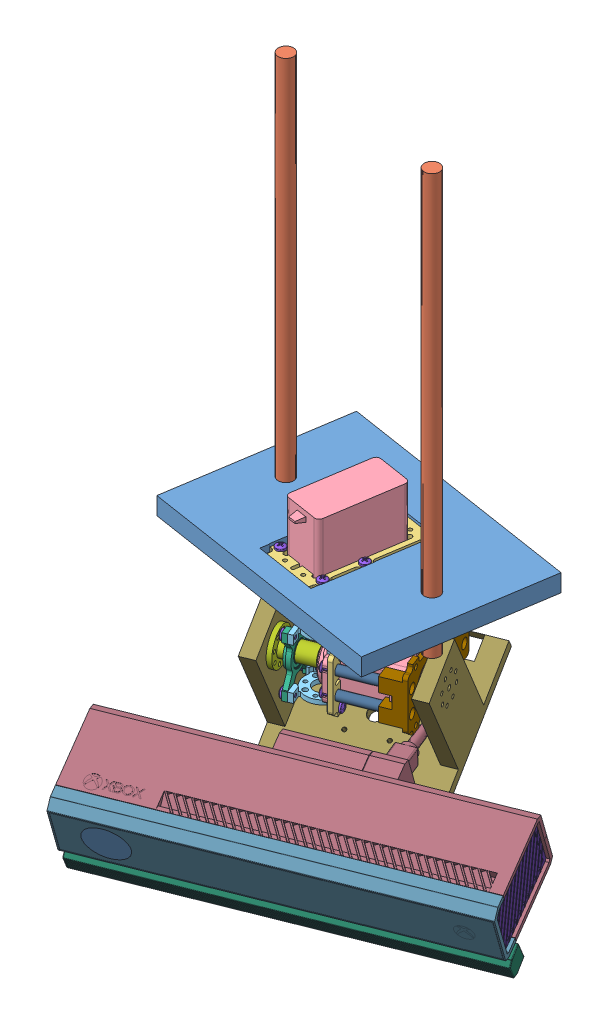
SolidWorks assembly kinectmount_v1, configuration Default. Lengths in mm.
Overall size (283.46 444.76 247.38).
58 component instances, 20 part files, 32 mates.
Components (placement in the parent):
- v1top_plate_support_1-1: v1top_plate_support_1 [Default] at (32.3217 110.1138 129.0138) x (0.98817 0 0.153364) z (-0.153364 0 0.98817) size (177.8 12.7 127)
- v1hangingrod-1: v1hangingrod [Default] at (95.0705 237.1138 138.7524) x (0.364647 0 0.931146) z (-0.931146 0 0.364647) size (11.11 304.8 11.11)
- v1hangingrod-2: v1hangingrod [Default] at (-30.4271 237.1138 119.2752) x (0.048421 0 0.998827) z (-0.998827 0 0.048421) size (11.11 304.8 11.11)
- v1637118-1: v1637118 [Default] at (30.752 120.9088 153.6804) x (-0.98817 0 -0.153364) z (-0.153364 0 0.98817) size (44.45 77.81 79.38) (flexible)
  - v1575116-1: v1575116 [Default] at origin size (44.45 3.17 79.38)
  - v1Servo HS755-1: v1Servo HS755 [Default] at (14.2177 -7.7317 -24.4001) x (-1 0 0) z (0 0 -1) size (28.47 55.59 73.84)
  - v1545420-1: v1545420 [Default] at (-21.463 15.875 0) x (0 -1 0) z (0 0 1) size (25.4 6.35 33.02)
  - v1545420-2: v1545420 [Default] at (21.463 15.875 0) x (0 1 0) z (0 0 1) size (25.4 6.35 33.02)
  - v1535182-1: v1535182 [Default] at (0 28.575 -0.0043) size (42.93 5.08 33.3)
  - v1525123-1: v1525123 [Default] at (0 38.9128 -0.0043) x (0.968651 0 -0.248427) z (0.248427 0 0.968651) size (25.4 25.4 25.4)
  - pan cross head_ai-1: pan cross head_ai [CR-PHMS 0.138-32x0.25x0.25-N] at (-18.288 34.2138 13.4704) x (0 -1 0) z (0 0 1) size (8.77 6.86 6.86)
  - pan cross head_ai-2: pan cross head_ai [CR-PHMS 0.138-32x0.25x0.25-N] at (18.288 34.2138 13.4704) x (0 -1 0) z (0 0 1) size (8.77 6.86 6.86)
  - pan cross head_ai-3: pan cross head_ai [CR-PHMS 0.138-32x0.25x0.25-N] at (18.288 34.2138 -13.479) x (0 -1 0) z (0 0 1) size (8.77 6.86 6.86)
  - pan cross head_ai-4: pan cross head_ai [CR-PHMS 0.138-32x0.25x0.25-N] at (-18.288 34.2138 -13.479) x (0 -1 0) z (0 0 1) size (8.77 6.86 6.86)
  - pan cross head_ai-5: pan cross head_ai [CR-PHMS 0.138-32x0.25x0.25-N] at (-7.9375 9.6393 -49.7649) x (0 -1 0) z (0 0 1) size (8.77 6.86 6.86) (hidden)
  - pan cross head_ai-6: pan cross head_ai [CR-PHMS 0.138-32x0.25x0.25-N] at (7.8994 9.6393 -49.7649) x (0 -1 0) z (0 0 1) size (8.77 6.86 6.86) (hidden)
  - pan cross head_ai-7: pan cross head_ai [CR-PHMS 0.138-32x0.25x0.25-N] at (-7.9375 9.6393 18.2563) x (0 -1 0) z (0 0 1) size (8.77 6.86 6.86) (hidden)
  - pan cross head_ai-8: pan cross head_ai [CR-PHMS 0.138-32x0.25x0.25-N] at (7.8994 9.6393 18.2563) x (0 -1 0) z (0 0 1) size (8.77 6.86 6.86) (hidden)
  - pan cross head_ai-9: pan cross head_ai [CR-PHMS 0.138-32x0.25x0.25-N] at (-18.288 -2.4638 -13.4704) x (0 1 0) z (0 0 1) size (8.77 6.86 6.86)
  - pan cross head_ai-10: pan cross head_ai [CR-PHMS 0.138-32x0.25x0.25-N] at (-18.288 -2.4638 13.4704) x (0 1 0) z (0 0 1) size (8.77 6.86 6.86)
  - pan cross head_ai-11: pan cross head_ai [CR-PHMS 0.138-32x0.25x0.25-N] at (18.288 -2.4638 -13.4704) x (0 1 0) z (0 0 1) size (8.77 6.86 6.86)
  - pan cross head_ai-12: pan cross head_ai [CR-PHMS 0.138-32x0.25x0.25-N] at (18.288 -2.4638 13.4704) x (0 1 0) z (0 0 1) size (8.77 6.86 6.86)
- v1637118-2: v1637118 [Default] at (45.493 57.358 147.7823) x (0 1 0) z (0.371265 0 0.928527) size (44.45 77.81 79.38) (flexible)
  - v1575116-1: v1575116 [Default] at origin size (44.45 3.17 79.38)
  - v1Servo HS755-1: v1Servo HS755 [Default] at (14.2177 -7.7317 -24.4001) x (-1 0 0) z (0 0 -1) size (28.47 55.59 73.84)
  - v1545420-1: v1545420 [Default] at (-21.463 15.875 0) x (0 -1 0) z (0 0 1) size (25.4 6.35 33.02)
  - v1545420-2: v1545420 [Default] at (21.463 15.875 0) x (0 1 0) z (0 0 1) size (25.4 6.35 33.02)
  - v1535182-1: v1535182 [Default] at (0 28.575 -0.0043) size (42.93 5.08 33.3)
  - v1525123-1: v1525123 [Default] at (0 38.9128 -0.0043) x (0.962665 0 -0.270696) z (0.270696 0 0.962665) size (25.4 25.4 25.4)
  - pan cross head_ai-1: pan cross head_ai [CR-PHMS 0.138-32x0.25x0.25-N] at (-18.288 34.2138 13.4704) x (0 -1 0) z (0 0 1) size (8.77 6.86 6.86)
  - pan cross head_ai-2: pan cross head_ai [CR-PHMS 0.138-32x0.25x0.25-N] at (18.288 34.2138 13.4704) x (0 -1 0) z (0 0 1) size (8.77 6.86 6.86)
  - pan cross head_ai-3: pan cross head_ai [CR-PHMS 0.138-32x0.25x0.25-N] at (18.288 34.2138 -13.479) x (0 -1 0) z (0 0 1) size (8.77 6.86 6.86)
  - pan cross head_ai-4: pan cross head_ai [CR-PHMS 0.138-32x0.25x0.25-N] at (-18.288 34.2138 -13.479) x (0 -1 0) z (0 0 1) size (8.77 6.86 6.86)
  - pan cross head_ai-5: pan cross head_ai [CR-PHMS 0.138-32x0.25x0.25-N] at (-7.9375 9.6393 -49.7649) x (0 -1 0) z (0 0 1) size (8.77 6.86 6.86)
  - pan cross head_ai-6: pan cross head_ai [CR-PHMS 0.138-32x0.25x0.25-N] at (7.8994 9.6393 -49.7649) x (0 -1 0) z (0 0 1) size (8.77 6.86 6.86)
  - pan cross head_ai-7: pan cross head_ai [CR-PHMS 0.138-32x0.25x0.25-N] at (-7.9375 9.6393 18.2563) x (0 -1 0) z (0 0 1) size (8.77 6.86 6.86)
  - pan cross head_ai-8: pan cross head_ai [CR-PHMS 0.138-32x0.25x0.25-N] at (7.8994 9.6393 18.2563) x (0 -1 0) z (0 0 1) size (8.77 6.86 6.86)
  - pan cross head_ai-9: pan cross head_ai [CR-PHMS 0.138-32x0.25x0.25-N] at (-18.288 -2.4638 -13.4704) x (0 1 0) z (0 0 1) size (8.77 6.86 6.86)
  - pan cross head_ai-10: pan cross head_ai [CR-PHMS 0.138-32x0.25x0.25-N] at (-18.288 -2.4638 13.4704) x (0 1 0) z (0 0 1) size (8.77 6.86 6.86)
  - pan cross head_ai-11: pan cross head_ai [CR-PHMS 0.138-32x0.25x0.25-N] at (18.288 -2.4638 -13.4704) x (0 1 0) z (0 0 1) size (8.77 6.86 6.86)
  - pan cross head_ai-12: pan cross head_ai [CR-PHMS 0.138-32x0.25x0.25-N] at (18.288 -2.4638 13.4704) x (0 1 0) z (0 0 1) size (8.77 6.86 6.86)
- v1575116_backside-1: v1575116_backside [Default] at (84.4076 57.358 132.2226) x (0 1 0) z (0.371265 0 0.928527) size (44.45 16.51 79.38)
- v1standoff_1in-1: v1standoff_1in [Default] at (75.8555 65.2955 155.3036) x (0.371265 -0.000659 0.928527) z (-0.000245 -1 -0.000612) size (6.35 25.4 6.35)
- v1standoff_1in-2: v1standoff_1in [Default] at (50.6016 49.4205 92.1441) x (-0.33977 -0.40307 -0.849759) z (-0.149646 0.915169 -0.374261) size (6.35 25.4 6.35)
- v1standoff_1in-3: v1standoff_1in [Default] at (50.6016 65.2955 92.1441) x (0.371265 -0.000659 0.928527) z (-0.000245 -1 -0.000612) size (6.35 25.4 6.35)
- v1standoff_1in-4: v1standoff_1in [Default] at (75.8555 49.4205 155.3036) x (0.371265 -0.000659 0.928527) z (-0.000245 -1 -0.000612) size (6.35 25.4 6.35)
- v1disc-1: v1disc [Default] at (84.406 57.358 132.2186) x (-0.047607 0.991745 -0.119063) z (-0.3682 -0.128228 -0.920862) size (25.4 2.54 25.4)
- pan cross head_ai-2: pan cross head_ai [CR-PHMS 0.138-32x0.25x0.25-N] at (79.1702 57.358 134.3121) x (0.928527 0 -0.371265) z (0.072297 0.980857 0.180812) size (8.77 6.86 6.86)
- v1Part3-1: v1Part3 [Default] at (35.0006 2.2927 117.915) x (0.928527 0 -0.371265) z (0.32195 -0.498012 0.805191) size (106.68 82.55 167.64)
- v1AS1-1: v1AS1 [Default] at (63.7505 -33.1271 189.818) x (-0.928527 0 0.371265) z (0.184895 0.86717 0.462418) size (250 121.83 65.49)
  - v11-1: v11 [Default] at (-125 41.8074 21.2837) x (0 0.993094 0.117321) z (1 0 0) size (114.6 50.3 250)
  - v12-1: v12 [Default] at (-125 28.1027 19.6646) x (0 0.993094 0.117321) z (1 0 0) size (13.8 43 250)
  - v13-1: v13 [Default] at origin size (250 82 32.5)
  - v14-1: v14 [Default] at (120 -21.7062 17.6613) x (0 0.993094 0.117321) z (1 0 0) size (60.5 37 3)
  - v15-1: v15 [Default] at (-120 -21.7062 17.6613) x (0 0.993094 0.117321) z (1 0 0) size (60.5 37 3)
  - v16-1: v16 [Default] at (0 -32.2685 30.3556) x (1 0 0) z (0 -0.993094 -0.117321) size (44 36 8)
  - v17-1: v17 [Default] at (95 36.4213 41.3048) x (-1 0 0) z (0 0.993094 0.117321) size (28 28 3)
  - v18-1: v18 [Default] at (95 31.9524 40.7769) x (-1 0 0) z (0 0.993094 0.117321) size (12 12 4)
Mates (geometry in assembly coordinates):
- Concentric1: concentric aligned: cylinder of v1top_plate_support_1-1 through (-30.4271 122.8138 119.2752) axis (0 -1 0) radius 5.588; cylinder of v1hangingrod-2 through (-30.4271 389.5138 119.2752) axis (0 -1 0) radius 5.5563
- Concentric2: concentric aligned: cylinder of v1top_plate_support_1-1 through (95.0705 122.8138 138.7524) axis (0 -1 0) radius 5.588; cylinder of v1hangingrod-1 through (95.0705 389.5138 138.7524) axis (0 -1 0) radius 5.5563
- Distance1: distance = 25.4 mm aligned: plane of v1hangingrod-2 through (-30.4271 84.7138 119.2752) normal (0 -1 0); plane of v1top_plate_support_1-1 through (32.3217 110.1138 129.0138) normal (0 -1 0)
- Distance3: distance = 25.4 mm aligned: plane of v1hangingrod-1 through (95.0705 84.7138 138.7524) normal (0 -1 0); plane of v1top_plate_support_1-1 through (32.3217 110.1138 129.0138) normal (0 -1 0)
- Coincident4: coincident anti-aligned: plane of v1637118-1/v1575116-1 through (30.752 117.7338 153.6804) normal (0 -1 0); plane of v1top_plate_support_1-1 through (32.3217 117.7338 129.0138) normal (0 1 0)
- Concentric3: concentric aligned: cylinder of v1top_plate_support_1-1 through (20.1462 122.8138 170.5092) axis (0 -1 0) radius 1.4605; cylinder of v1637118-1/pan cross head_ai-8 through (20.1462 85.8695 170.5092) axis (0 -1 0) radius 1.7526
- Parallel2: parallel aligned: plane of v1top_plate_support_1-1 through (-45.788 122.8138 52.631) normal (0.153364 0 -0.98817); plane of v1637118-1/v1Servo HS755-1 through (23.616 111.1171 106.9546) normal (0.153364 0 -0.98817)
- Concentric7: concentric aligned: cylinder of v1637118-1/v1525123-1 through (34.3833 78.821 162.7562) axis (0 -1 0) radius 1.3526; cylinder of v1637118-2/v1545420-2 through (34.3833 75.646 162.7562) axis (0 -1 0) radius 1.3526
- Concentric8: concentric aligned: cylinder of v1637118-1/v1525123-1 through (27.1221 78.821 144.5961) axis (0 -1 0) radius 1.3526; cylinder of v1637118-2/v1545420-2 through (27.1221 75.646 144.5961) axis (0 -1 0) radius 1.3526
- Coincident7: coincident anti-aligned: plane of v1637118-1/v1525123-1 through (30.7527 78.821 153.6761) normal (0 -1 0); plane of v1637118-2/v1545420-2 through (12.8308 78.821 143.0612) normal (0 1 0)
- Parallel3: parallel anti-aligned: plane of ? through (61.9286 71.5756 92.6621) normal (0.928527 0 -0.371265); plane of v1575116_backside-1 through (81.4595 57.358 133.4013) normal (-0.928527 0 0.371265)
- Concentric11: concentric anti-aligned: cylinder of v1637118-2/v1575116-1 through (52.2709 49.4205 164.7337) axis (0.928527 0 -0.371265) radius 1.3526; cylinder of v1standoff_1in-4 through (52.2709 49.4205 164.7337) axis (-0.928527 0 0.371265) radius 1.3526
- Concentric12: concentric anti-aligned: cylinder of v1575116_backside-1 through (75.8555 65.2955 155.3036) axis (0.928527 0 -0.371265) radius 1.397; cylinder of v1standoff_1in-1 through (52.2709 65.2955 164.7337) axis (-0.928527 0 0.371265) radius 1.3526
- Concentric13: concentric anti-aligned: cylinder of v1575116_backside-1 through (50.6016 65.2955 92.1441) axis (0.928527 0 -0.371265) radius 1.397; cylinder of v1standoff_1in-3 through (27.017 65.2955 101.5742) axis (-0.928527 0 0.371265) radius 1.3526
- Concentric14: concentric anti-aligned: cylinder of v1575116_backside-1 through (50.6016 49.4205 92.1441) axis (0.928527 0 -0.371265) radius 1.397; cylinder of v1standoff_1in-2 through (27.017 49.4205 101.5742) axis (-0.928527 0 0.371265) radius 1.3526
- Coincident9: coincident anti-aligned: plane of v1637118-2/v1575116-1 through (45.493 57.358 147.7823) normal (0.928527 0 -0.371265); plane of v1standoff_1in-1 through (52.2709 65.2955 164.7337) normal (-0.928527 0 0.371265)
- Coincident10: coincident anti-aligned: plane of v1637118-2/v1575116-1 through (45.493 57.358 147.7823) normal (0.928527 0 -0.371265); plane of v1standoff_1in-4 through (52.2709 49.4205 164.7337) normal (-0.928527 0 0.371265)
- Coincident11: coincident anti-aligned: plane of v1637118-2/v1575116-1 through (45.493 57.358 147.7823) normal (0.928527 0 -0.371265); plane of v1standoff_1in-2 through (27.017 49.4205 101.5742) normal (-0.928527 0 0.371265)
- Coincident12: coincident anti-aligned: plane of v1637118-2/v1575116-1 through (45.493 57.358 147.7823) normal (0.928527 0 -0.371265); plane of v1standoff_1in-3 through (27.017 65.2955 101.5742) normal (-0.928527 0 0.371265)
- Concentric15: concentric anti-aligned: cylinder of v1637118-2/v1575116-1 through (27.017 49.4205 101.5742) axis (0.928527 0 -0.371265) radius 1.3526; cylinder of v1standoff_1in-2 through (27.017 49.4205 101.5742) axis (-0.928527 0 0.371265) radius 1.3526
- Symmetric1: symmetric aligned: cylinder of v1637118-2/v1575116-1 through (52.2709 65.2955 164.7337) axis (0.928527 0 -0.371265) radius 1.3526; cylinder of v1standoff_1in-1 through (52.2709 65.2955 164.7337) axis (-0.928527 0 0.371265) radius 1.3526; plane of v1575116_backside-1 through (84.4076 57.358 132.2226) normal (0.928527 0 -0.371265)
- Coincident14: coincident anti-aligned: plane of v1575116_backside-1 through (69.0776 57.358 138.3522) normal (-0.928527 0 0.371265); plane of v1standoff_1in-4 through (75.8555 49.4205 155.3036) normal (0.928527 0 -0.371265)
- Concentric16: concentric anti-aligned: cylinder of v1575116_backside-1 through (81.4579 57.358 133.3973) axis (0.928527 0 -0.371265) radius 2.3812; cylinder of v1disc-1 through (86.7645 57.358 131.2756) axis (-0.928527 0 0.371265) radius 1.7859
- Coincident15: coincident anti-aligned: plane of v1575116_backside-1 through (84.4076 57.358 132.2226) normal (0.928527 0 -0.371265); plane of v1disc-1 through (84.406 57.358 132.2186) normal (-0.928527 0 0.371265)
- Concentric17: concentric aligned: cylinder of v1disc-1 through (86.7645 57.358 131.2756) axis (-0.928527 0 0.371265) radius 1.7859; cylinder of pan cross head_ai-2 through (55.5856 57.358 143.7422) axis (-0.928527 0 0.371265) radius 1.7526
- Coincident16: coincident anti-aligned: plane of v1575116_backside-1 through (81.4595 57.358 133.4013) normal (-0.928527 0 0.371265); plane of pan cross head_ai-2 through (80.8197 57.6993 131.8011) normal (0.928527 0 -0.371265)
- Coincident19: coincident anti-aligned: plane of v1637118-2/v1525123-1 through (6.4118 57.358 163.404) normal (-0.928527 0 0.371265); plane of v1Part3-1 through (3.8009 83.3647 156.8742) normal (0.928527 0 -0.371265)
- Concentric26: concentric aligned: cylinder of v1637118-2/v1525123-1 through (29.9973 57.358 153.9735) axis (-0.928527 0 0.371265) radius 1.6; cylinder of v1Part3-1 through (96.269 57.358 127.4752) axis (-0.928527 0 0.371265) radius 1.7859
- Concentric27: concentric aligned: cylinder of pan cross head_ai-2 through (55.5856 57.358 143.7422) axis (-0.928527 0 0.371265) radius 1.7526; cylinder of v1Part3-1 through (96.269 57.358 127.4752) axis (-0.928527 0 0.371265) radius 1.7859
- Coincident20: coincident anti-aligned: plane of v1Part3-1 through (54.5741 -20.6622 166.868) normal (0.184895 0.86717 0.462418); plane of v1AS1-1/v13-1 through (63.4732 -34.4278 189.1244) normal (-0.184895 -0.86717 -0.462418)
- Concentric29: concentric aligned: cylinder of v1Part3-1 through (66.3707 -38.9099 196.3711) axis (-0.184895 -0.86717 -0.462418) radius 3.175; cylinder of v1AS1-1/v13-1 through (66.6481 -37.6092 197.0647) axis (-0.184895 -0.86717 -0.462418) radius 2.5527
- Parallel8: parallel aligned: plane of v1Part3-1 through (-31.7524 36.2606 94.638) normal (-0.32195 0.498012 -0.805191); plane of v1AS1-1/v13-1 through (51.4751 -8.3727 159.1173) normal (-0.32195 0.498012 -0.805191)
